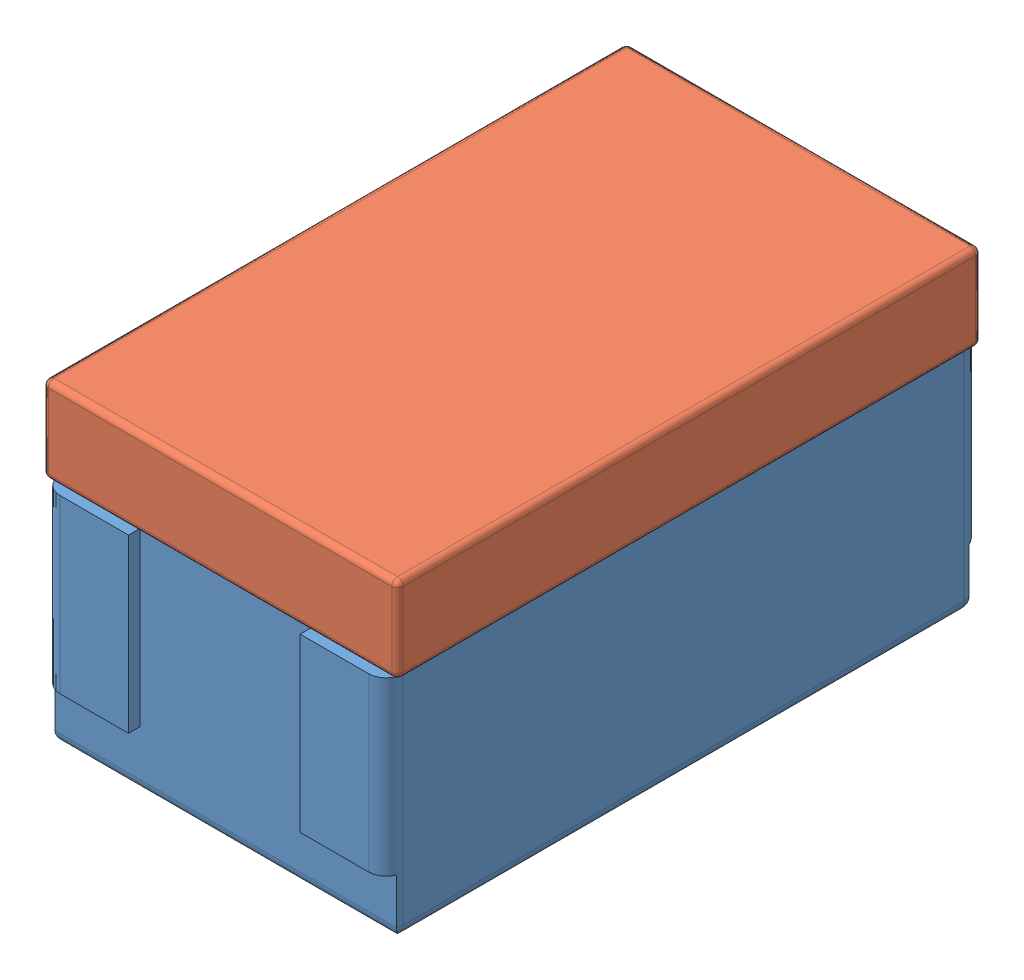
SolidWorks assembly caja entera 20186156, configuration Default. Lengths in mm.
Overall size (62 55.23 104).
2 component instances, 2 part files, 2 mates.
Components (placement in the parent):
- caja20186256-1: caja20186256 [Default] at (34.6146 30.1855 98.4129) size (60 50 104)
- cajatapa20186256-1: cajatapa20186256 [Default] at (34.6146 85.4144 98.4129) x (0 0 1) z (1 0 0) size (102 15 62)
Mates (geometry in assembly coordinates):
- Width1: width anti-aligned: plane of cajatapa20186256-1 through (4.6146 83.4144 48.4129) normal (1 0 0); plane of caja20186256-1 through (64.6146 83.4144 48.4129) normal (-1 0 0); plane of cajatapa20186256-1 through (4.6146 80.1855 148.4129) normal (-1 0 0); plane of caja20186256-1 through (64.6146 80.1855 148.4129) normal (1 0 0)
- Width2: width anti-aligned: plane of cajatapa20186256-1 through (64.6146 83.4144 48.4129) normal (0 0 1); plane of caja20186256-1 through (64.6146 83.4144 148.4129) normal (0 0 -1); plane of cajatapa20186256-1 through (4.6146 80.1855 48.4129) normal (0 0 -1); plane of caja20186256-1 through (4.6146 80.1855 148.4129) normal (0 0 1)
